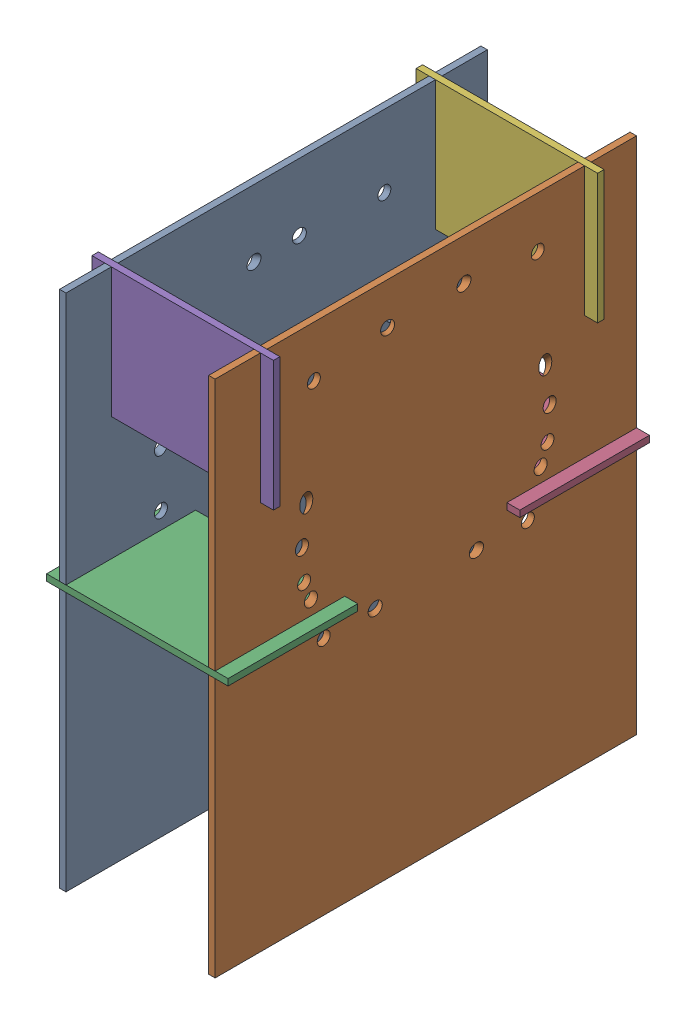
SolidWorks assembly Teal Team Jig Assembly, configuration Default. Lengths in mm.
Overall size (2625.4 1667.85 825.5).
7 component instances, 7 part files, 18 mates.
Components (placement in the parent):
- University_of_Portland_Chassis_006-1: University_of_Portland_Chassis_006 [Default<As Machined>] at origin size (2625.4 1211.08 727.61) (suppressed, hidden)
- Teal_1-1: Teal_1 [Default] at (374.65 38.1 0) x (0 0 -1) z (1 0 0) size (825.5 1016 12.7)
- Teal_2-1: Teal_2 [Default] at (666.75 38.1 0) x (0 0 -1) z (1 0 0) size (825.5 1016 12.7)
- Teal_3-1: Teal_3 [Default] at (520.7 44.45 285.75) size (355.6 12.7 254)
- Teal_4-1: Teal_4 [Default] at (520.7 44.45 -285.75) x (-1 0 0) z (0 0 -1) size (355.6 12.7 254)
- Teal_5-1: Teal_5 [Default] at (-951.304 570.2799 317.5) size (355.6 254 12.7)
- Teal_6-2: Teal_6 [Default] at (-951.304 570.2799 -317.5) size (355.6 254 12.7)
Mates (geometry in assembly coordinates):
- Distance1: distance = 685.8 mm anti-aligned: plane of Teal Jig 2-1 through (673.1 38.1 0) normal (1 0 0)
- Distance2: distance = 457.2 mm aligned: plane of Teal Jig 2-1 through (673.1 -469.9 412.75) normal (0 -1 0)
- Coincident4: coincident: point of Teal Jig 2-1
- Distance3: distance = 457.2 mm aligned: plane of Teal Jig 1-1 through (381 -469.9 412.75) normal (0 -1 0)
- Distance4: distance = 381 mm aligned: plane of Teal Jig 1-1 through (368.3 38.1 0) normal (-1 0 0)
- Coincident8: coincident: unknown of Teal Jig 1-1
- Distance5: distance = 50.8 mm aligned: plane of teal jig 3-1 through (520.7 38.1 285.75) normal (0 -1 0)
- Coincident10: coincident aligned: plane of Teal Jig 1-1 through (381 546.1 412.75) normal (0 0 1); plane of teal jig 3-1 through (342.9 50.8 412.75) normal (0 0 1)
- Distance6: distance = 25.4 mm aligned: plane of teal jig 3-1 through (342.9 50.8 158.75) normal (-1 0 0); plane of Teal Jig 1-1 through (368.3 38.1 0) normal (-1 0 0)
- Coincident16: coincident aligned: plane of Teal Jig 1-1 through (381 546.1 -412.75) normal (0 0 -1); plane of teal jig 4-1 through (698.5 50.8 -412.75) normal (0 0 -1)
- Distance8: distance = 25.4 mm aligned: plane of teal jig 4-1 through (342.9 50.8 -158.75) normal (-1 0 0); plane of Teal Jig 1-1 through (368.3 38.1 0) normal (-1 0 0)
- Coincident18: coincident aligned: plane of teal jig 3-1 through (520.7 50.8 285.75) normal (0 1 0); plane of teal jig 4-1 through (520.7 50.8 -285.75) normal (0 1 0)
- Coincident19: coincident aligned: plane of Teal Jig 1-1 through (381 546.1 412.75) normal (0 1 0); plane of Teal Jig 5-1 through (342.9 546.1 323.85) normal (0 1 0)
- Coincident21: coincident anti-aligned: plane of Teal Jig 1-1 through (381 546.1 311.15) normal (0 0 1); plane of Teal Jig 5-1 through (-951.304 570.2799 311.15) normal (0 0 -1)
- Coincident22: coincident anti-aligned: plane of Teal Jig 1-1 through (368.3 38.1 0) normal (-1 0 0); plane of Teal Jig 5-1 through (368.3 292.1 323.85) normal (1 0 0)
- Coincident23: coincident anti-aligned: plane of Teal Jig 1-1 through (381 546.1 -311.15) normal (0 0 -1); plane of Teal Jig 5-2 through (-951.304 570.2799 -311.15) normal (0 0 1)
- Coincident24: coincident anti-aligned: plane of Teal Jig 2-1 through (673.1 38.1 0) normal (1 0 0); plane of Teal Jig 5-2 through (673.1 419.1 -311.15) normal (-1 0 0)
- Coincident25: coincident aligned: plane of Teal Jig 2-1 through (673.1 546.1 412.75) normal (0 1 0); plane of Teal Jig 5-2 through (342.9 546.1 -311.15) normal (0 1 0)
